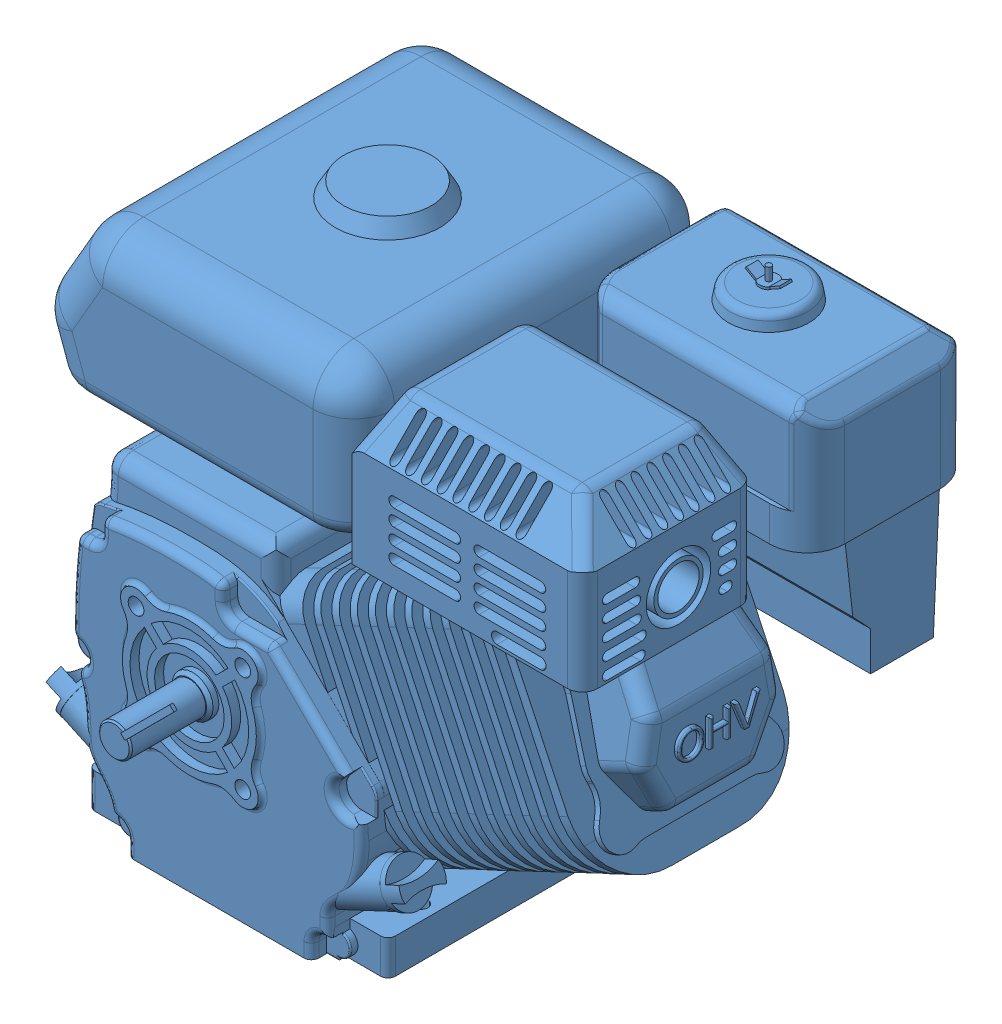
SolidWorks assembly ДВИГАТЕЛЬ, configuration По умолчанию. Lengths in mm.
Overall size (355.98 333.63 313.38).
2 component instances, 2 part files, 2 mates.
Components (placement in the parent):
- ДВИГАТЕЛЬ 6,5-1: ДВИГАТЕЛЬ 6,5 [По умолчанию] at origin size (355.98 333.63 313.38)
- БАК-1: БАК [По умолчанию] at (432.2252 1729.3613 -4.7246) x (-1 0 0) z (0 0 -1) size (197.52 99 220) (hidden)
Mates (geometry in assembly coordinates):
- Совпадение2: coincident aligned: plane of ДВИГАТЕЛЬ 6,5-1 through (449.1545 1716.1067 -224.7246) normal (0 0 -1); plane of БАК-1 through (432.2252 1729.3613 -224.7246) normal (0 0 -1)
- Расстояние1: distance = 30 mm anti-aligned: plane of ДВИГАТЕЛЬ 6,5-1 through (337.8554 1609.3613 -215.965) normal (0 1 0); plane of БАК-1 through (244.9642 1639.3613 -224.7246) normal (0 -1 0)
